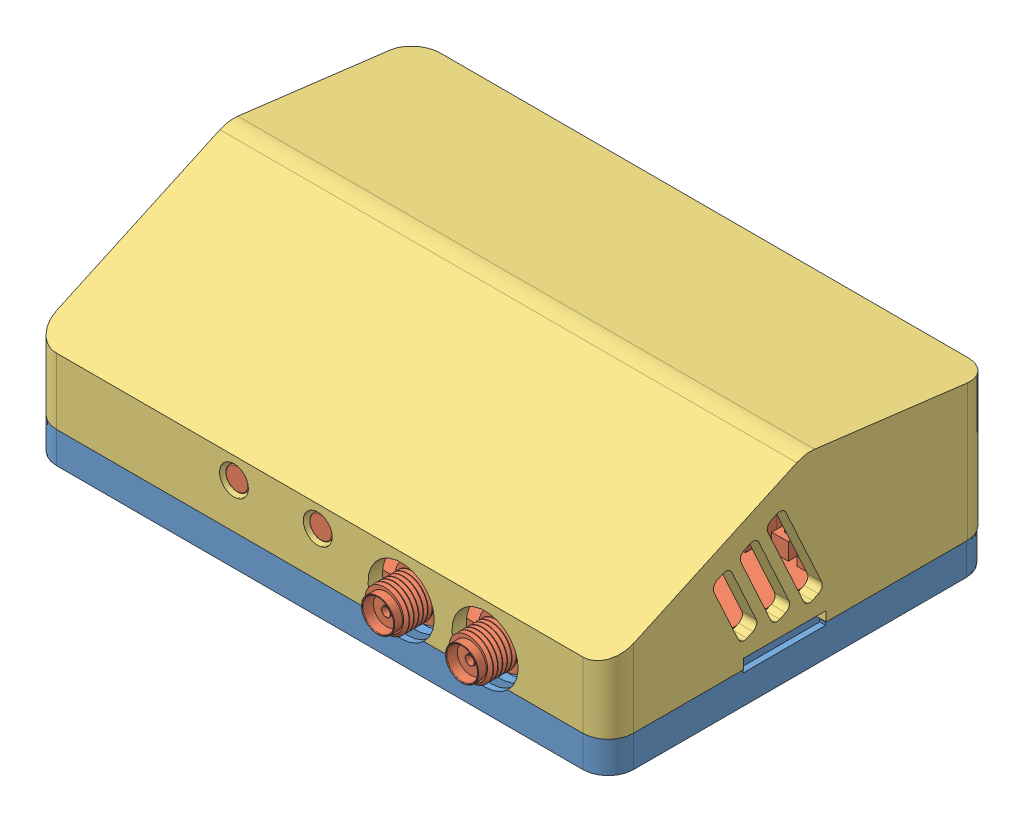
SolidWorks assembly gateway_in_case, configuration Default. Lengths in mm.
Overall size (87.3 28.33 61.85).
3 component instances, 3 part files, 5 mates.
Components (placement in the parent):
- case_bottom-1: case_bottom [Default] at (26.4502 48.3602 68.3445) size (87.3 6.22 58)
- edison_gateway-1: edison_gateway [Default] at (-8.6235 55.8621 89.7639) x (1 0 0) z (0 1 0) size (80.14 58.7 18.58)
- case_top-1: case_top [Default] at (35.7386 51.3302 67.5928) x (-1 0 0) z (0 0 -1) size (87.3 23.56 58.2)
Mates (geometry in assembly coordinates):
- Concentric2: concentric anti-aligned: circle of case_bottom-1; circle of edison_gateway-1
- Coincident3: coincident anti-aligned: plane of case_bottom-1 through (26.4502 54.5802 68.3445) normal (0 1 0); plane of edison_gateway-1 through (-8.6235 54.5802 82.0778) normal (0 -1 0)
- Concentric3: concentric aligned: circle of case_bottom-1; circle of edison_gateway-1
- Coincident7: coincident anti-aligned: plane of case_bottom-1 through (71.2315 53.1302 39.1639) normal (0 1 0); plane of case_top-1 through (35.7386 53.1302 67.5928) normal (0 -1 0)
- Distance2: distance = 0.6 mm: plane of case_top-1 through (70.3552 53.1302 91.8639) normal (0 0 1); plane of case_bottom-1 through (-8.4685 53.1302 92.4639) normal (0 0 -1)
